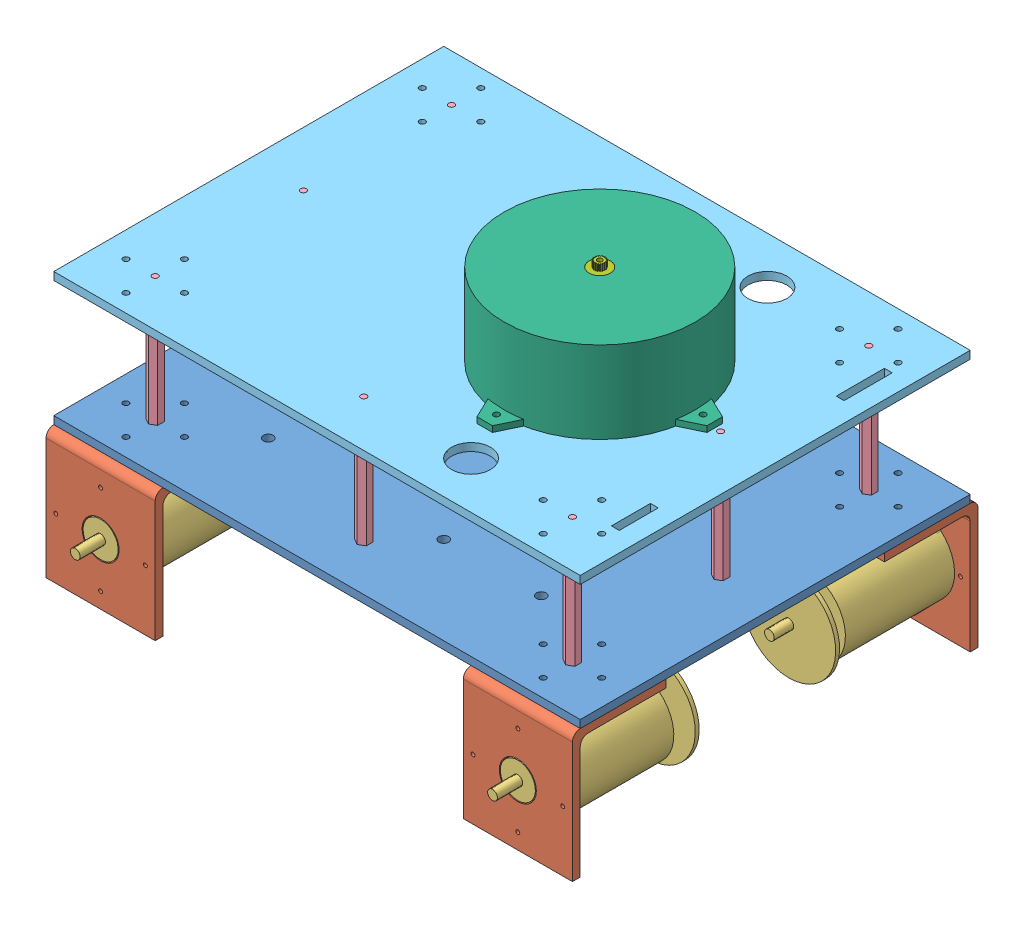
SolidWorks assembly robot_config5 - Copy, configuration Default. Lengths in mm.
Overall size (270 179.13 234).
20 component instances, 7 part files, 37 mates.
Components (placement in the parent):
- base_odroid_down_fix-1: base_odroid_down_fix [Default] at (39.4639 122.941 229.7749) x (1 0 0) z (0 -1 0) size (270 200 4)
- link_motor_1_port-1: link_motor_1_port [Default] at (221.3654 112.3394 287.3354) x (0 0 -1) z (1 0 0) size (48 66 56)
- motor_dc_NISCA-1: motor_dc_NISCA [Default] at (244.2642 39.7289 313.6416) x (0 -1 0) z (0 0 -1) size (54 48 92)
- link_motor_1_port-2: link_motor_1_port [Default] at (221.3654 112.3394 139.9479) x (0 0 1) z (-1 0 0) size (48 66 56)
- motor_dc_NISCA-2: motor_dc_NISCA [Default] at (198.4666 39.7289 113.6416) x (0 -1 0) z (0 0 1) size (54 48 92)
- link_motor_1_port-5: link_motor_1_port [Default] at (7.3654 112.3394 287.3354) x (0 0 -1) z (1 0 0) size (48 66 56)
- motor_dc_NISCA-5: motor_dc_NISCA [Default] at (-15.5334 128.1531 313.6416) x (0 1 0) z (0 0 -1) size (54 48 92)
- link_motor_1_port-6: link_motor_1_port [Default] at (7.3654 112.3394 139.9479) x (0 0 1) z (-1 0 0) size (48 66 56)
- motor_dc_NISCA-6: motor_dc_NISCA [Default] at (-15.5334 39.7289 113.6416) x (0 -1 0) z (0 0 1) size (54 48 92)
- spacer_6cm-2: spacer_6cm [Default] at (221.7099 182.941 288.7798) x (0.5 0 -0.866025) z (0 -1 0) size (6 6.93 68)
- spacer_6cm-3: spacer_6cm [Default] at (114.7099 182.941 288.7798) x (0.5 0 -0.866025) z (0 -1 0) size (6 6.93 68)
- spacer_6cm-4: spacer_6cm [Default] at (7.7099 182.941 288.7798) x (0.5 0 -0.866025) z (0 -1 0) size (6 6.93 68)
- spacer_6cm-5: spacer_6cm [Default] at (221.7099 182.941 212.7798) x (0.5 0 -0.866025) z (0 -1 0) size (6 6.93 68)
- spacer_6cm-7: spacer_6cm [Default] at (7.7099 182.941 212.7798) x (0.5 0 -0.866025) z (0 -1 0) size (6 6.93 68)
- spacer_6cm-8: spacer_6cm [Default] at (221.7099 182.941 136.7798) x (0.5 0 -0.866025) z (0 -1 0) size (6 6.93 68)
- spacer_6cm-9: spacer_6cm [Default] at (114.7099 182.941 136.7798) x (0.5 0 -0.866025) z (0 -1 0) size (6 6.93 68)
- spacer_6cm-10: spacer_6cm [Default] at (7.7099 182.941 136.7798) x (0.5 0 -0.866025) z (0 -1 0) size (6 6.93 68)
- base_odroid_up_fix-1: base_odroid_up_fix [Default] at (186.1287 186.941 197.5083) x (-1 0 0) z (0 -1 0) size (270 200 4)
- base_arm-1: base_arm [Default] at (159.3654 194.0898 219.4289) x (0 0 1) z (-1 0 0) size (118.01 42 118.01)
- servo_hs422-1: servo_hs422 [Default] at (169.6524 210.6756 203.7356) x (0 0 1) z (-1 0 0) size (19.81 42.14 58.23)
Mates (geometry in assembly coordinates):
- Coincident1: coincident anti-aligned: plane of link_motor_1_port-1 through (193.3654 52.941 313.6416) normal (0 0 -1); plane of motor_dc_NISCA-1 through (221.3654 83.941 313.6416) normal (0 0 1)
- Concentric1: concentric aligned: cylinder of link_motor_1_port-1 through (221.3654 83.941 317.6416) axis (0 0 -1) radius 9.5; cylinder of motor_dc_NISCA-1 through (221.3654 83.941 317.6416) axis (0 0 -1) radius 9
- Concentric2: concentric anti-aligned: cylinder of link_motor_1_port-1 through (221.3654 106.941 317.6416) axis (0 0 -1) radius 1; cylinder of motor_dc_NISCA-1 through (221.3654 106.941 311.6416) axis (0 0 1) radius 1.5
- Coincident8: coincident anti-aligned: plane of link_motor_1_port-2 through (249.3654 52.941 113.6416) normal (0 0 1); plane of motor_dc_NISCA-2 through (221.3654 83.941 113.6416) normal (0 0 -1)
- Concentric5: concentric aligned: cylinder of link_motor_1_port-2 through (221.3654 83.941 109.6416) axis (0 0 1) radius 9.5; cylinder of motor_dc_NISCA-2 through (221.3654 83.941 109.6416) axis (0 0 1) radius 9
- Concentric7: concentric anti-aligned: cylinder of link_motor_1_port-2 through (221.3654 106.941 109.6416) axis (0 0 1) radius 1; cylinder of motor_dc_NISCA-2 through (221.3654 106.941 115.6416) axis (0 0 -1) radius 1.5
- Coincident9: coincident anti-aligned: plane of base_odroid_down_fix-1 through (39.4639 118.941 229.7749) normal (0 -1 0); plane of link_motor_1_port-1 through (193.3654 118.941 269.6416) normal (0 1 0)
- Concentric8: concentric anti-aligned: cylinder of base_odroid_down_fix-1 through (206.3654 118.941 289.6416) axis (0 1 0) radius 1.5; cylinder of link_motor_1_port-1 through (206.3654 118.941 289.6416) axis (0 -1 0) radius 1.5
- Concentric9: concentric anti-aligned: cylinder of base_odroid_down_fix-1 through (236.3654 118.941 289.6416) axis (0 1 0) radius 1.5; cylinder of link_motor_1_port-1 through (236.3654 118.941 289.6416) axis (0 -1 0) radius 1.5
- Coincident15: coincident anti-aligned: plane of base_odroid_down_fix-1 through (39.4639 118.941 229.7749) normal (0 -1 0); plane of link_motor_1_port-2 through (249.3654 118.941 157.6416) normal (0 1 0)
- Concentric11: concentric anti-aligned: cylinder of base_odroid_down_fix-1 through (206.3654 118.941 137.6416) axis (0 1 0) radius 1.5; cylinder of link_motor_1_port-2 through (206.3654 118.941 137.6416) axis (0 -1 0) radius 1.5
- Concentric12: concentric anti-aligned: cylinder of base_odroid_down_fix-1 through (236.3654 118.941 137.6416) axis (0 1 0) radius 1.5; cylinder of link_motor_1_port-2 through (236.3654 118.941 137.6416) axis (0 -1 0) radius 1.5
- Coincident16: coincident anti-aligned: plane of link_motor_1_port-5 through (-20.6346 52.941 313.6416) normal (0 0 -1); plane of motor_dc_NISCA-5 through (7.3654 83.941 313.6416) normal (0 0 1)
- Concentric13: concentric aligned: cylinder of link_motor_1_port-5 through (7.3654 83.941 317.6416) axis (0 0 -1) radius 9.5; cylinder of motor_dc_NISCA-5 through (7.3654 83.941 317.6416) axis (0 0 -1) radius 9
- Concentric14: concentric anti-aligned: cylinder of link_motor_1_port-5 through (7.3654 106.941 317.6416) axis (0 0 -1) radius 1; cylinder of motor_dc_NISCA-5 through (7.3654 106.941 311.6416) axis (0 0 1) radius 1.5
- Coincident21: coincident anti-aligned: plane of base_odroid_down_fix-1 through (39.4639 118.941 229.7749) normal (0 -1 0); plane of link_motor_1_port-5 through (-20.6346 118.941 269.6416) normal (0 1 0)
- Concentric17: concentric anti-aligned: cylinder of base_odroid_down_fix-1 through (-7.6346 118.941 289.6416) axis (0 1 0) radius 1.5; cylinder of link_motor_1_port-5 through (-7.6346 118.941 289.6416) axis (0 -1 0) radius 1.5
- Concentric18: concentric anti-aligned: cylinder of base_odroid_down_fix-1 through (22.3654 118.941 289.6416) axis (0 1 0) radius 1.5; cylinder of link_motor_1_port-5 through (22.3654 118.941 289.6416) axis (0 -1 0) radius 1.5
- Coincident22: coincident anti-aligned: plane of link_motor_1_port-6 through (35.3654 52.941 113.6416) normal (0 0 1); plane of motor_dc_NISCA-6 through (7.3654 83.941 113.6416) normal (0 0 -1)
- Concentric19: concentric aligned: cylinder of link_motor_1_port-6 through (7.3654 83.941 109.6416) axis (0 0 1) radius 9.5; cylinder of motor_dc_NISCA-6 through (7.3654 83.941 109.6416) axis (0 0 1) radius 9
- Concentric20: concentric anti-aligned: cylinder of link_motor_1_port-6 through (7.3654 106.941 109.6416) axis (0 0 1) radius 1; cylinder of motor_dc_NISCA-6 through (7.3654 106.941 115.6416) axis (0 0 -1) radius 1.5
- Coincident27: coincident anti-aligned: plane of base_odroid_down_fix-1 through (39.4639 118.941 229.7749) normal (0 -1 0); plane of link_motor_1_port-6 through (35.3654 118.941 157.6416) normal (0 1 0)
- Concentric22: concentric anti-aligned: cylinder of base_odroid_down_fix-1 through (-7.6346 118.941 137.6416) axis (0 1 0) radius 1.5; cylinder of link_motor_1_port-6 through (-7.6346 118.941 137.6416) axis (0 -1 0) radius 1.5
- Concentric23: concentric anti-aligned: cylinder of base_odroid_down_fix-1 through (22.3654 118.941 137.6416) axis (0 1 0) radius 1.5; cylinder of link_motor_1_port-6 through (22.3654 118.941 137.6416) axis (0 -1 0) radius 1.5
- Concentric24: concentric aligned: cylinder of base_odroid_down_fix-1 through (221.3654 118.941 289.6416) axis (0 1 0) radius 1.5; cylinder of spacer_6cm-2 through (221.3654 118.941 289.6416) axis (0 1 0) radius 1.5
- Coincident28: coincident anti-aligned: plane of base_odroid_down_fix-1 through (39.4639 122.941 229.7749) normal (0 1 0); plane of spacer_6cm-2 through (221.7099 122.941 288.7798) normal (0 -1 0)
- Parallel2: parallel aligned: plane of base_odroid_down_fix-1 through (249.3654 118.941 229.7749) normal (1 0 0); plane of spacer_6cm-2 through (224.3654 122.941 287.9096) normal (1 0 0)
- Concentric25: concentric anti-aligned: cylinder of spacer_6cm-2 through (221.3654 186.941 289.6416) axis (0 -1 0) radius 1.5; cylinder of base_odroid_up_fix-1 through (221.3654 182.941 289.6416) axis (0 1 0) radius 1.5
- Concentric26: concentric anti-aligned: cylinder of spacer_6cm-7 through (7.3654 186.941 213.6416) axis (0 -1 0) radius 1.5; cylinder of base_odroid_up_fix-1 through (7.3654 182.941 213.6416) axis (0 1 0) radius 1.5
- Coincident29: coincident anti-aligned: plane of spacer_6cm-2 through (221.7099 182.941 288.7798) normal (0 1 0); plane of base_odroid_up_fix-1 through (186.1287 182.941 197.5083) normal (0 -1 0)
- Coincident31: coincident anti-aligned: plane of base_arm-1 through (159.3654 225.941 213.6416) normal (0 -1 0); plane of servo_hs422-1 through (169.6524 225.941 203.7356) normal (0 1 0)
- Parallel3: parallel aligned: plane of base_odroid_up_fix-1 through (249.3654 182.941 197.5083) normal (1 0 0); plane of servo_hs422-1 through (189.5914 210.6756 223.5476) normal (1 0 0)
- Coincident33: coincident anti-aligned: plane of base_odroid_up_fix-1 through (186.1287 186.941 197.5083) normal (0 1 0); plane of base_arm-1 through (159.3654 186.941 259.6416) normal (0 -1 0)
- Concentric28: concentric anti-aligned: cylinder of base_odroid_up_fix-1 through (212.3654 182.941 213.6416) axis (0 1 0) radius 1.5; cylinder of base_arm-1 through (212.3654 189.941 213.6416) axis (0 -1 0) radius 1.5
- Concentric29: concentric anti-aligned: cylinder of base_odroid_up_fix-1 through (159.3654 182.941 160.6416) axis (0 1 0) radius 1.5; cylinder of base_arm-1 through (159.3654 189.941 160.6416) axis (0 -1 0) radius 1.5
- Parallel5: parallel aligned: plane of base_odroid_up_fix-1 through (186.1287 182.941 113.6416) normal (0 0 -1); plane of servo_hs422-1 through (169.6524 210.6756 203.7356) normal (0 0 -1)
- Concentric30: concentric aligned: cylinder of base_arm-1 through (159.3654 225.941 213.6416) axis (0 1 0) radius 5.4623; cylinder of servo_hs422-1 through (159.3654 202.0734 213.6416) axis (0 1 0) radius 6.4897
